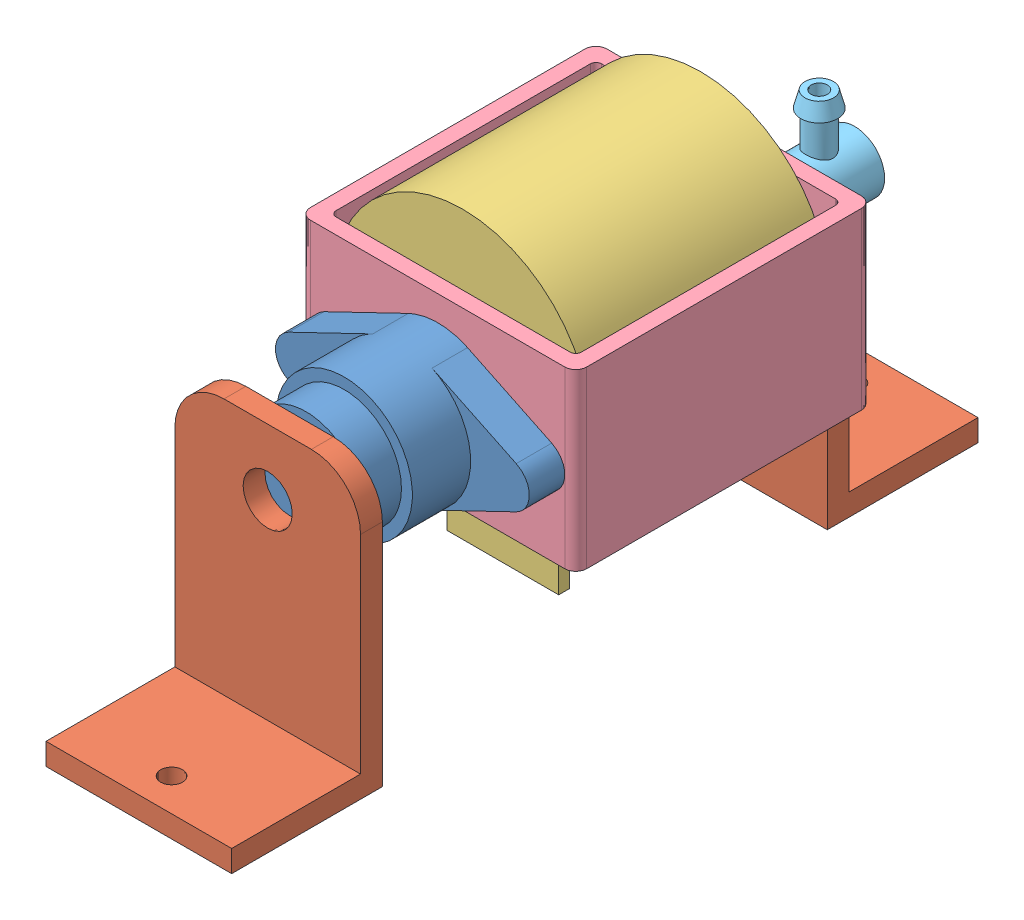
SolidWorks assembly ulkaPump, configuration Default. Lengths in mm.
Overall size (50.6 66.66 136.68).
6 component instances, 5 part files, 6 mates.
Components (placement in the parent):
- pumpConnector-1: pumpConnector [Default] at (-0.7849 39 13.5713) size (46.5 25 27.17)
- pumpHolder-1: pumpHolder [Default] at (-0.7849 0 54.5393) size (34 51 27.6)
- pumpHolder-2: pumpHolder [Default] at (-0.7849 0 -54.5393) x (-1 0 0) z (0 0 -1) size (34 51 27.6)
- pumpHousing-1: pumpHousing [Default] at (-1.3746 43.1623 -13.3528) size (47 52.39 43.6)
- pumpFrame-1: pumpFrame [Default] at (-0.8394 24.0944 -13.5787) size (50.6 32 54.3)
- pumpInputConnector-1: pumpInputConnector [Default] at (-0.7849 39 -44.7393) size (11 20.04 18)
Mates (geometry in assembly coordinates):
- Coincident1: coincident anti-aligned: plane of pumpHolder-1 through (-0.7849 0 54.5393) normal (0 -1 0)
- Concentric5: concentric anti-aligned: cylinder of pumpConnector-1 through (-0.7849 39 40.7393) axis (0 0 -1) radius 7; cylinder of pumpHolder-1 through (-0.7849 39 40.7393) axis (0 0 1) radius 4.5
- Coincident2: coincident anti-aligned: plane of pumpConnector-1 through (-0.7849 39 40.7393) normal (0 0 1); plane of pumpHolder-1 through (-17.7849 4 40.7393) normal (0 0 -1)
- Coincident5: coincident anti-aligned: plane of pumpConnector-1 through (-19.7849 39 13.5713) normal (0 0 -1); plane of pumpFrame-1 through (-26.1394 56.0944 13.5713) normal (0 0 1)
- Concentric6: concentric anti-aligned: circle of pumpHolder-2; circle of pumpTubeConnector-1
- Coincident7: coincident anti-aligned: plane of pumpHolder-2 through (16.2151 51 -44.7393) normal (0 0 -1); plane of pumpTubeConnector-1 through (-0.7849 39 -44.7393) normal (0 0 1)
